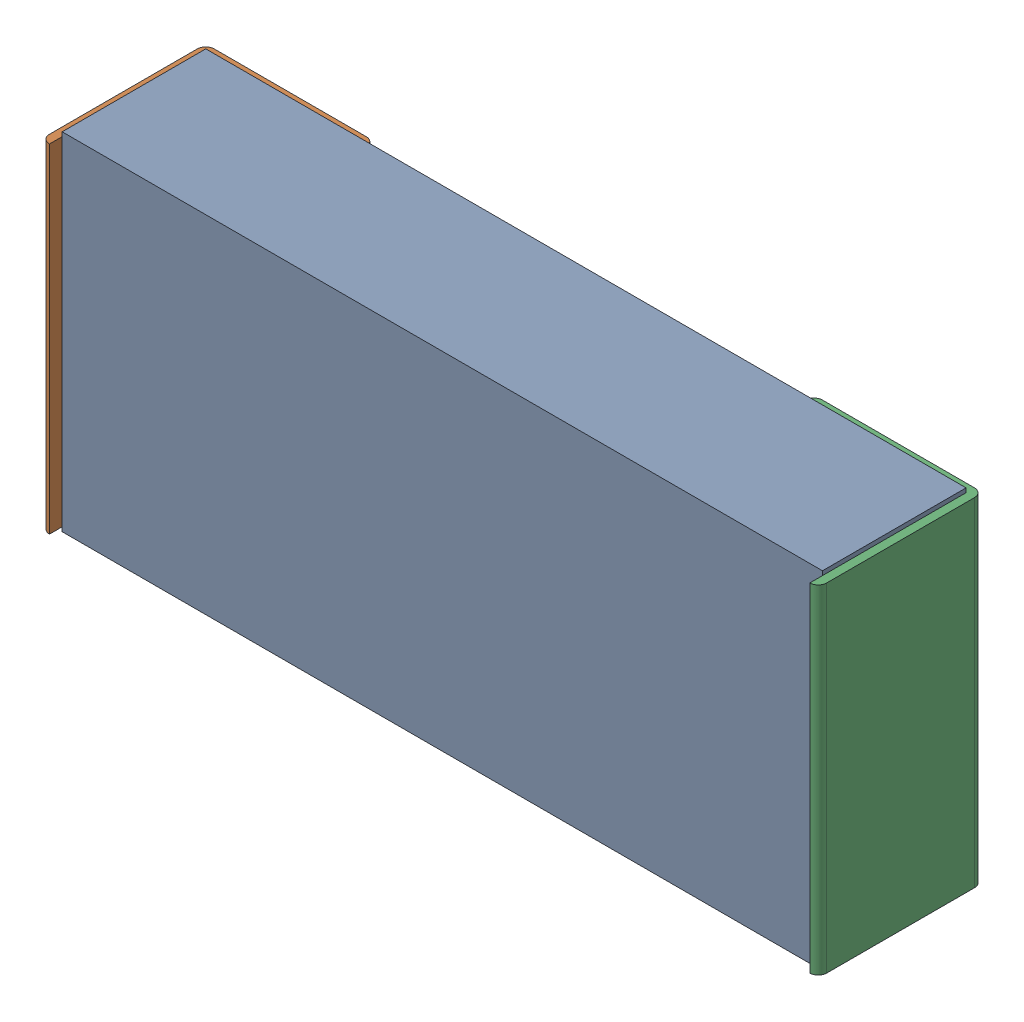
SolidWorks assembly C2, configuration Predeterminado. Lengths in mm.
Overall size (2.34 1.04 0.5).
4 component instances, 3 part files, 0 mates.
Components (placement in the parent):
- Open CASCADE STEP translator 6.8 1.5.1-1: Open CASCADE STEP translator 6.8 1.5.1 [Predeterminado] at origin size (2.34 1.04 0.5)
  - Body_1_2-1: Body_1_2 [Predeterminado] at origin size (2.29 1.04 0.43)
  - Pin_1_2-1: Pin_1_2 [Predeterminado] at (0.3048 0 0) x (-1 0 0) z (0 0 1) size (0.51 1.02 0.5)
  - Pin_2_2-1: Pin_2_2 [Predeterminado] at origin size (0.51 1.02 0.5)
